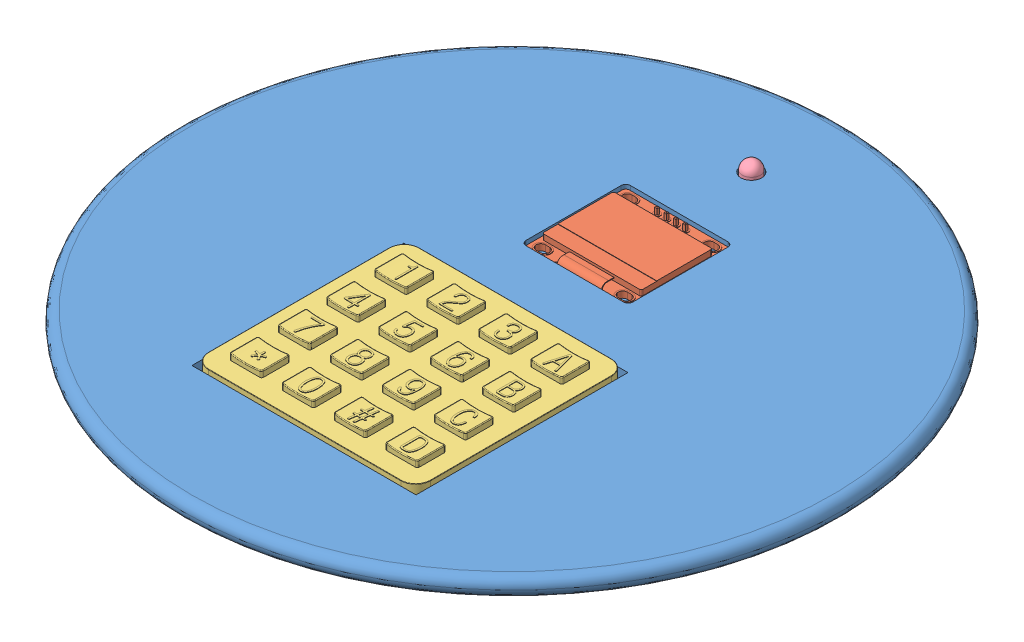
SolidWorks assembly Top, configuration Default. Lengths in mm.
Overall size (177.8 15 177.8).
4 component instances, 4 part files, 9 mates.
Components (placement in the parent):
- Middle-1: Middle [1] at (70.3126 90.2499 126.1956) size (177.8 5.08 177.8)
- OLED Screen-1: OLED Screen [Default] at (70.3126 94.3899 95.5906) x (1 0 0) z (0 1 0) size (28.3 27.65 10.4)
- Keypad-1: Keypad [Výchozí] at (70.3126 89.2899 153.6906) x (1 0 0) z (0 1 0) size (65 69 8.87)
- RBG Module-1: RBG Module [Default] at (70.3126 83.4999 61.6156) x (-0.000001 0 1) z (-1 0 -0.000001) size (15 15 24.23)
Mates (geometry in assembly coordinates):
- Coincident1: coincident anti-aligned: plane of Middle-1 through (57.1626 92.7899 82.3406) normal (0 1 0); plane of OLED Screen-1 through (70.3126 92.7899 95.1656) normal (0 -1 0)
- Width1: width aligned: plane of OLED Screen-1 through (56.9726 94.3899 85.4656) normal (-1 0 0); plane of OLED Screen-1 through (83.6526 94.3899 104.6656) normal (1 0 0); plane of Middle-1 through (84.7166 92.7899 107.9906) normal (-1 0 0); plane of Middle-1 through (55.9086 92.7899 82.3406) normal (1 0 0)
- Width2: width anti-aligned: plane of OLED Screen-1 through (56.1626 94.3899 81.3406) normal (0 0 -1); plane of OLED Screen-1 through (84.4626 94.3899 108.9906) normal (0 0 1); plane of Middle-1 through (83.4626 92.7899 81.0866) normal (0 0 1); plane of Middle-1 through (76.9626 92.7899 109.2446) normal (0 0 -1)
- Width3: width anti-aligned: plane of KlavesniceTlacitkovaSolid-1 through (96.2626 96.4899 125.2906) normal (0 0 -1); plane of KlavesniceTlacitkovaSolid-1 through (44.3626 96.4899 182.0906) normal (0 0 1); plane of Middle-1 through (40.0866 95.3299 125.1156) normal (0 0 1); plane of Middle-1 through (40.0866 95.3299 182.2656) normal (0 0 -1)
- Width4: width anti-aligned: plane of Middle-1 through (100.5386 95.3299 182.2656) normal (-1 0 0); plane of Middle-1 through (40.0866 95.3299 182.2656) normal (1 0 0); plane of KlavesniceTlacitkovaSolid-1 through (100.2626 96.4899 178.0906) normal (1 0 0); plane of KlavesniceTlacitkovaSolid-1 through (40.3626 96.4899 129.2906) normal (-1 0 0)
- Coincident2: coincident anti-aligned: plane of Middle-1 through (70.3126 92.7899 126.1956) normal (0 -1 0); plane of KlavesniceTlacitkovaSolid-1 through (40.3126 92.7899 183.1906) normal (0 1 0)
- Concentric1: concentric aligned: cylinder of Middle-1 through (70.3126 82.3473 61.6156) axis (0 1 0) radius 2.794; cylinder of RBG Module-1 through (70.3126 93.0249 61.6156) axis (0 1 0) radius 2.45
- Coincident3: coincident anti-aligned: plane of Middle-1 through (70.3126 90.2499 126.1956) normal (0 -1 0); plane of RBG Module-1 through (70.3126 90.2499 59.1656) normal (0 1 0)
- Concentric2: concentric aligned: cylinder of Middle-1 through (77.1626 92.7899 56.7656) axis (0 -1 0) radius 0.635; cylinder of RBG Module-1 through (77.1626 84.9999 56.7656) axis (0 -1 0) radius 1.15
